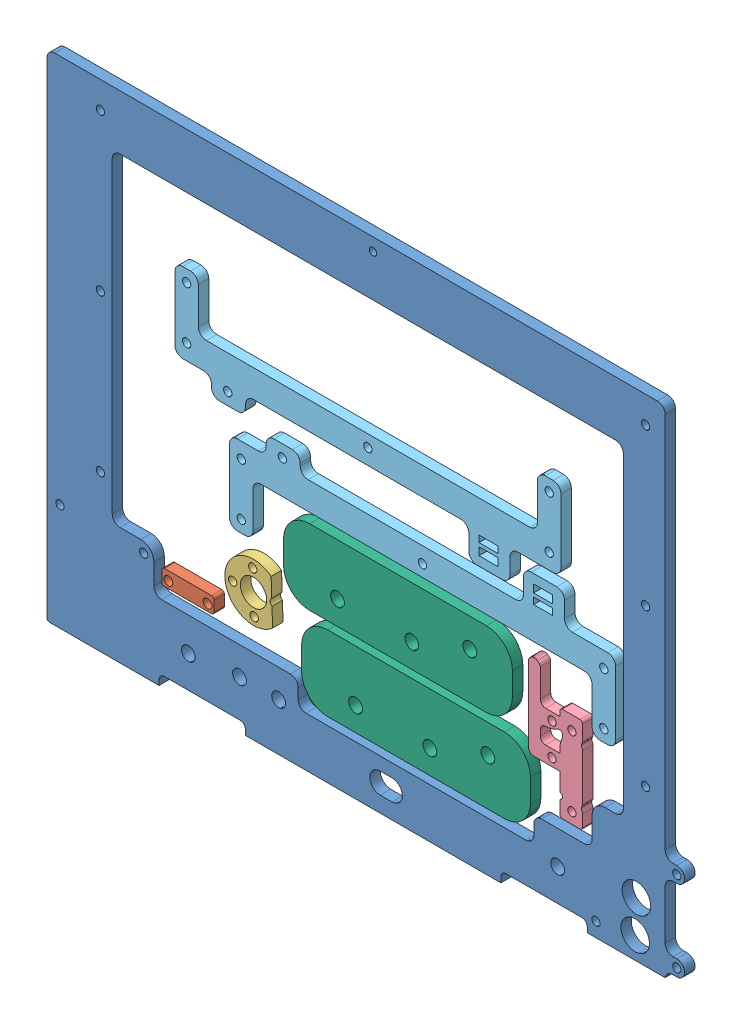
SolidWorks assembly Z AND Y FRAME PLUS SMALL ONES, configuration Default. Lengths in mm.
Overall size (255.05 200 4.2).
8 component instances, 6 part files, 16 mates.
Components (placement in the parent):
- Mini CF Main Frame external3-1: Mini CF Main Frame external3 [Valor predeterminado] at (-101.6268 37.5207 24.9892) size (250 190 4)
- Copy (2) of Part4-2: Copy (2) of Part4 [Valor predeterminado] at (-107.0018 -101.8637 -108.3764) size (20 6.02 4)
- Mini CF Z nut atachment-2: Mini CF Z nut atachment [Valor predeterminado] at (195.66 62.1672 24.7929) x (0.034129 -0.999417 0) z (0 0 1) size (22 18.05 4)
- Extruder stopper2-2: Extruder stopper2 [Valor predeterminado] at (13.7705 -47.9934 28.9892) x (0 1 0) z (0 0 -1) size (48.08 20.7 4)
- TABLE2-1: TABLE2 [Valor predeterminado] at (-32.9971 -240.0309 28.9892) x (1 0 0) z (0 0 -1) size (148 42.68 4)
- Small foot-1: Small foot [Default] at (-364.3985 16.4839 24.9892) x (0 1 0) z (0 0 1) size (28.8 87.75 4)
- Small foot-2: Small foot [Default] at (-357.4739 -15.319 24.9892) x (0 1 0) z (0 0 1) size (28.8 87.75 4)
- TABLE2-3: TABLE2 [Valor predeterminado] at (-53.9358 248.8215 24.9892) size (148 42.68 4)
Mates (geometry in assembly coordinates):
- Coincident19: coincident aligned: plane of Mini CF Main Frame external3-1 through (-172.3832 79.4051 27.9892) normal (0 0 1); plane of Extruder stopper2-2
- Distance22: distance = 5 mm anti-aligned: plane of Extruder stopper2-2 through (30.1715 54.4051 27.9892) normal (0 1 0); plane of Mini CF Main Frame external3-1 through (-147.3832 59.4051 27.9892) normal (0 -1 0)
- Distance25: distance = 3 mm anti-aligned: plane of Mini CF Main Frame external3-1 through (-153.3832 49.4051 27.9892) normal (1 0 0); plane of Copy (2) of Part4-2 through (-150.3832 -11.8428 27.9892) normal (-1 0 0)
- Coincident27: coincident aligned: plane of Mini CF Main Frame external3-1 through (-172.3832 79.4051 27.9892) normal (0 0 1); plane of Copy (2) of Part4-2 through (-109.2047 19.4849 27.9892) normal (0 0 1)
- Coincident32: coincident aligned: plane of Mini CF Main Frame external3-1 through (-172.3832 79.4051 27.9892) normal (0 0 1); plane of Mini CF Z nut atachment-2 through (11.8091 -2.8428 27.9892) normal (0 0 1)
- Coincident35: coincident aligned: plane of Mini CF Main Frame external3-1 through (-179.3832 86.4051 28.9892) normal (0 0 1); plane of TABLE2-1 through (-129.4464 -6.6764 28.9892) normal (0 0 1)
- Coincident38: coincident aligned: plane of Mini CF Main Frame external3-1 through (-179.3832 86.4051 28.9892) normal (0 0 1); plane of Extruder stopper2-2 through (13.7705 -47.9934 28.9892) normal (0 0 1)
- Coincident40: coincident aligned: plane of Mini CF Main Frame external3-1 through (-179.3832 86.4051 28.9892) normal (0 0 1); plane of Copy (2) of Part4-2 through (-107.0018 -101.8637 28.9892) normal (0 0 1)
- Coincident42: coincident aligned: plane of Mini CF Main Frame external3-1 through (-179.3832 86.4051 28.9892) normal (0 0 1); plane of Small foot-2 through (-357.4739 -15.319 28.9892) normal (0 0 1)
- Coincident43: coincident aligned: plane of Mini CF Main Frame external3-1 through (-179.3832 86.4051 28.9892) normal (0 0 1); plane of Small foot-1 through (-364.3985 16.4839 28.9892) normal (0 0 1)
- Distance37: distance = 3 mm anti-aligned: plane of Small foot-1 through (-91.6797 -46.792 28.9892) normal (0 -1 0); plane of Small foot-2 through (-84.7551 -49.792 28.9892) normal (0 1 0)
- Distance41: distance = 3 mm: cylinder of Small foot-1 through (-70.4656 -27.9892 28.9892) axis (0 0 -1) radius 10; cylinder of TABLE2-1 through (-85.5036 -22.5247 24.9892) axis (0 0 1) radius 3
- Distance43: distance = 3 mm anti-aligned: plane of TABLE2-1 through (35.6168 -11.238 34.9892) normal (1 0 0); plane of Mini CF Main Frame external3-1 through (38.6168 65.4622 28.9892) normal (-1 0 0)
- Coincident44: coincident aligned: plane of Mini CF Main Frame external3-1 through (-179.3832 86.4051 28.9892) normal (0 0 1); plane of TABLE2-3 through (-150.385 15.467 28.9892) normal (0 0 1)
- Distance44: distance = 2.5 mm: cylinder of Small foot-2 through (-74.7551 -68.5949 28.9892) axis (0 0 -1) radius 10; cylinder of Mini CF Main Frame external3-1 through (-89.0467 -74.5949 28.9892) axis (0 0 -1) radius 3
- Distance46: distance = 3 mm anti-aligned: plane of Mini CF Main Frame external3-1 through (-137.3832 -81.5949 28.9892) normal (0 1 0); plane of Small foot-2 through (-84.7551 -78.5949 28.9892) normal (0 -1 0)
